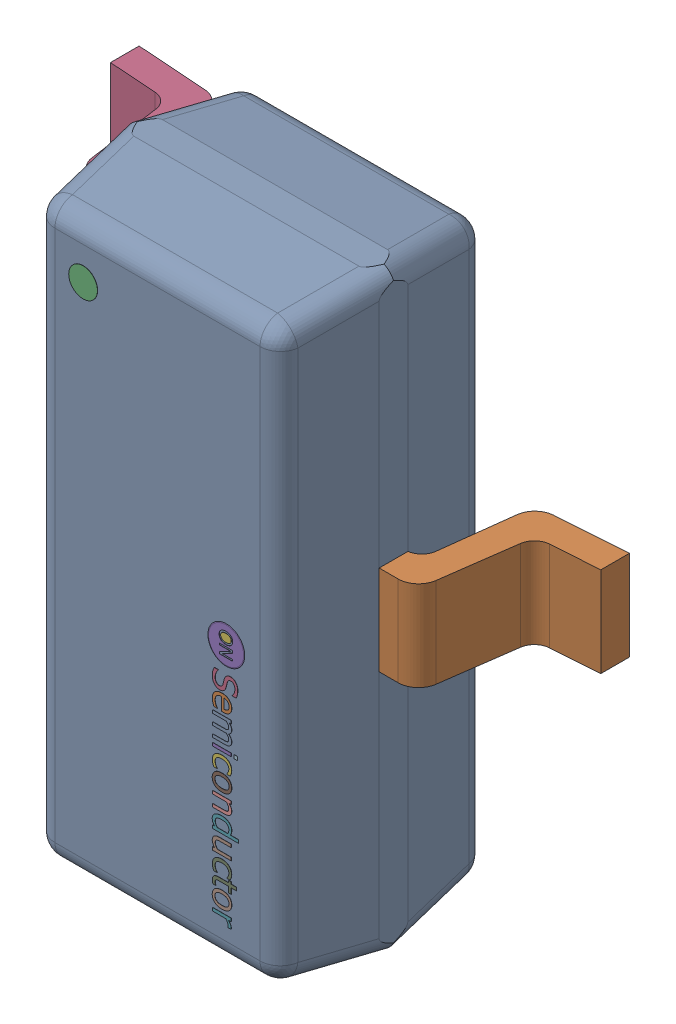
SolidWorks assembly Q2.step, configuration Default. Lengths in mm.
Overall size (2.4 2.9 1.11).
5 component instances, 4 part files, 0 mates.
Components (placement in the parent):
- IC_ON_Semiconductor_NUD3112LT1G_eec.step-1: IC_ON_Semiconductor_NUD3112LT1G_eec.step [Default] at (17.919 24.257 0) size (2.4 2.9 1.11)
  - 1-5.step-1: 1-5.step [Default] at (0 0 0.1) x (0 1 0) z (0 0 1) size (2.9 1.3 1.01)
  - 2-6.step-1: 2-6.step [Default] x (-1 0 0) z (0 1 0) size (2.4 0.68 2.34)
  - ON Semi Logo - withoutPN.step-1: ON Semi Logo - withoutPN.step [Default] at (-0.2581 -0.9018 1.011) x (-1 0 0) z (0 0 1) size (0.19 0.19 0.1)
  - ON Semi Logo - withoutPN - Copy.step-1: ON Semi Logo - withoutPN - Copy.step [Default] at (-0.2645 -0.8914 1.011) x (-1 0 0) z (0 0 1) size (0.83 2.45 0.1)
